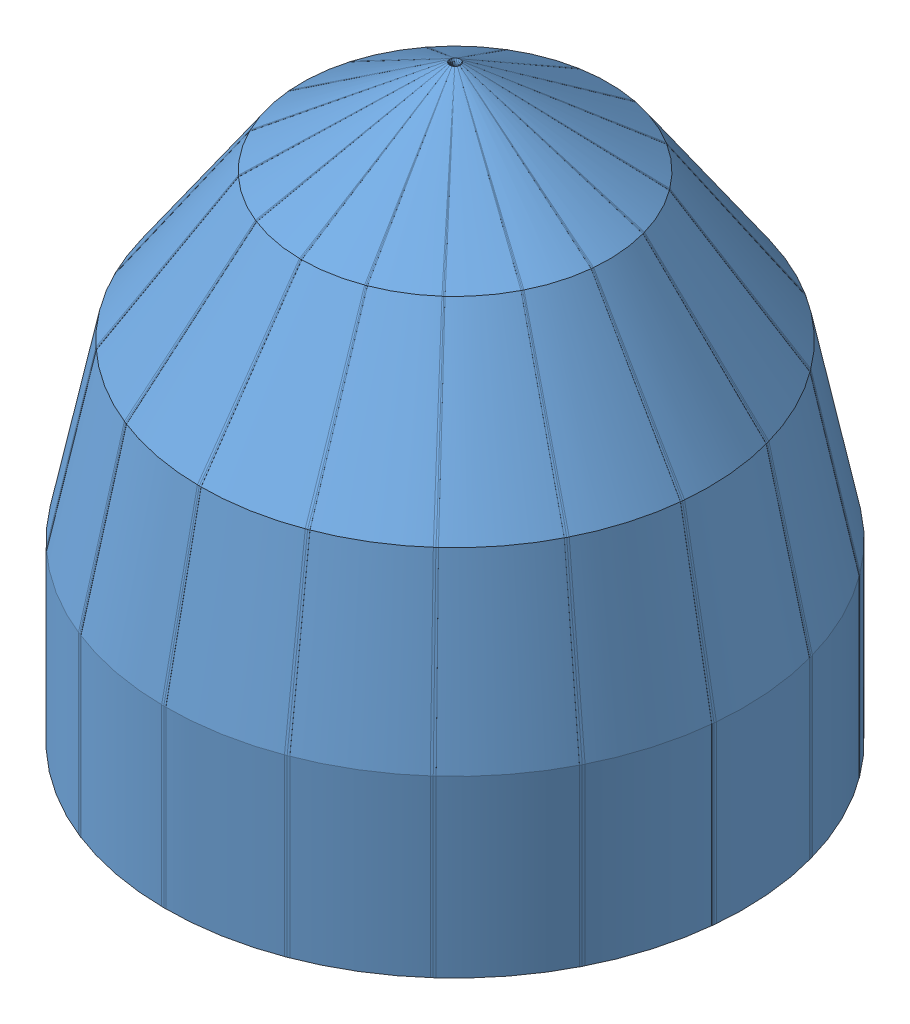
SolidWorks assembly Assem3, configuration Default. Lengths in mm.
Overall size (3151.78 3015.97 3141.58).
68 component instances, 3 part files, 0 mates.
Components (placement in the parent):
- Assem1-1: Assem1 [Default] at (1103.0345 -411.2974 -304.9237) size (563.93 3015.97 1482.16)
  - Part1-1: Part1 [Default] at (643.5811 535.4134 3088.0664) size (555.23 3015.97 1482.16)
  - steel 1-1: steel 1 [Default] at (103.5995 535.4134 2992.4104) x (0.927184 0 0.374607) z (-0.374607 0 0.927184) size (50 2898.58 1340.95)
  - steel 2-1: steel 2 [Default] at (643.5811 535.4134 3097.3722) x (0 0 -1) z (1 0 0) size (1340.95 2898.58 50)
- Assem1-2: Assem1 [Default] at (1744.6774 -411.2974 -425.5922) x (0.932472 0 0.361242) z (-0.361242 0 0.932472) size (563.93 3015.97 1482.16)
  - Part1-1: Part1 [Default] at (643.5811 535.4134 3088.0664) size (555.23 3015.97 1482.16)
  - steel 1-1: steel 1 [Default] at (103.5995 535.4134 2992.4104) x (0.927184 0 0.374607) z (-0.374607 0 0.927184) size (50 2898.58 1340.95)
  - steel 2-1: steel 2 [Default] at (643.5811 535.4134 3097.3722) x (0 0 -1) z (1 0 0) size (1340.95 2898.58 50)
- Assem1-3: Assem1 [Default] at (2386.5821 -411.2974 -306.3241) x (0.739009 0 0.673696) z (-0.673696 0 0.739009) size (563.93 3015.97 1482.16)
  - Part1-1: Part1 [Default] at (643.5811 535.4134 3088.0664) size (555.23 3015.97 1482.16)
  - steel 1-1: steel 1 [Default] at (103.5995 535.4134 2992.4104) x (0.927184 0 0.374607) z (-0.374607 0 0.927184) size (50 2898.58 1340.95)
  - steel 2-1: steel 2 [Default] at (643.5811 535.4134 3097.3722) x (0 0 -1) z (1 0 0) size (1340.95 2898.58 50)
- Assem1-4: Assem1 [Default] at (2942.0558 -411.2974 36.7729) x (0.445738 0 0.895163) z (-0.895163 0 0.445738) size (563.93 3015.97 1482.16)
  - Part1-1: Part1 [Default] at (643.5811 535.4134 3088.0664) size (555.23 3015.97 1482.16)
  - steel 1-1: steel 1 [Default] at (103.5995 535.4134 2992.4104) x (0.927184 0 0.374607) z (-0.374607 0 0.927184) size (50 2898.58 1340.95)
  - steel 2-1: steel 2 [Default] at (643.5811 535.4134 3097.3722) x (0 0 -1) z (1 0 0) size (1340.95 2898.58 50)
- Assem1-5: Assem1 [Default] at (3336.0786 -411.2974 557.3615) x (0.092268 0 0.995734) z (-0.995734 0 0.092268) size (563.93 3015.97 1482.16)
  - Part1-1: Part1 [Default] at (643.5811 535.4134 3088.0664) size (555.23 3015.97 1482.16)
  - steel 1-1: steel 1 [Default] at (103.5995 535.4134 2992.4104) x (0.927184 0 0.374607) z (-0.374607 0 0.927184) size (50 2898.58 1340.95)
  - steel 2-1: steel 2 [Default] at (643.5811 535.4134 3097.3722) x (0 0 -1) z (1 0 0) size (1340.95 2898.58 50)
- Assem1-6: Assem1 [Default] at (3515.4357 -411.2974 1185.1334) x (-0.273663 0 0.961826) z (-0.961826 0 -0.273663) size (563.93 3015.97 1482.16)
  - Part1-1: Part1 [Default] at (643.5811 535.4134 3088.0664) size (555.23 3015.97 1482.16)
  - steel 1-1: steel 1 [Default] at (103.5995 535.4134 2992.4104) x (0.927184 0 0.374607) z (-0.374607 0 0.927184) size (50 2898.58 1340.95)
  - steel 2-1: steel 2 [Default] at (643.5811 535.4134 3097.3722) x (0 0 -1) z (1 0 0) size (1340.95 2898.58 50)
- Assem1-7: Assem1 [Default] at (3455.9038 -411.2974 1835.3045) x (-0.602635 0 0.798017) z (-0.798017 0 -0.602635) size (563.93 3015.97 1482.16)
  - Part1-1: Part1 [Default] at (643.5811 535.4134 3088.0664) size (555.23 3015.97 1482.16)
  - steel 1-1: steel 1 [Default] at (103.5995 535.4134 2992.4104) x (0.927184 0 0.374607) z (-0.374607 0 0.927184) size (50 2898.58 1340.95)
  - steel 2-1: steel 2 [Default] at (643.5811 535.4134 3097.3722) x (0 0 -1) z (1 0 0) size (1340.95 2898.58 50)
- Assem1-8: Assem1 [Default] at (3165.5231 -411.2974 2420.0656) x (-0.850217 0 0.526432) z (-0.526432 0 -0.850217) size (563.93 3015.97 1482.16)
  - Part1-1: Part1 [Default] at (643.5811 535.4134 3088.0664) size (555.23 3015.97 1482.16)
  - steel 1-1: steel 1 [Default] at (103.5995 535.4134 2992.4104) x (0.927184 0 0.374607) z (-0.374607 0 0.927184) size (50 2898.58 1340.95)
  - steel 2-1: steel 2 [Default] at (643.5811 535.4134 3097.3722) x (0 0 -1) z (1 0 0) size (1340.95 2898.58 50)
- Assem1-9: Assem1 [Default] at (2683.5111 -411.2974 2860.4415) x (-0.982973 0 0.18375) z (-0.18375 0 -0.982973) size (563.93 3015.97 1482.16)
  - Part1-1: Part1 [Default] at (643.5811 535.4134 3088.0664) size (555.23 3015.97 1482.16)
  - steel 1-1: steel 1 [Default] at (103.5995 535.4134 2992.4104) x (0.927184 0 0.374607) z (-0.374607 0 0.927184) size (50 2898.58 1340.95)
  - steel 2-1: steel 2 [Default] at (643.5811 535.4134 3097.3722) x (0 0 -1) z (1 0 0) size (1340.95 2898.58 50)
- Assem1-10: Assem1 [Default] at (2074.9661 -411.2974 3096.9569) x (-0.982973 0 -0.18375) z (0.18375 0 -0.982973) size (563.93 3015.97 1482.16)
  - Part1-1: Part1 [Default] at (643.5811 535.4134 3088.0664) size (555.23 3015.97 1482.16)
  - steel 1-1: steel 1 [Default] at (103.5995 535.4134 2992.4104) x (0.927184 0 0.374607) z (-0.374607 0 0.927184) size (50 2898.58 1340.95)
  - steel 2-1: steel 2 [Default] at (643.5811 535.4134 3097.3722) x (0 0 -1) z (1 0 0) size (1340.95 2898.58 50)
- Assem1-11: Assem1 [Default] at (1422.0756 -411.2974 3097.6692) x (-0.850217 0 -0.526432) z (0.526432 0 -0.850217) size (563.93 3015.97 1482.16)
  - Part1-1: Part1 [Default] at (643.5811 535.4134 3088.0664) size (555.23 3015.97 1482.16)
  - steel 1-1: steel 1 [Default] at (103.5995 535.4134 2992.4104) x (0.927184 0 0.374607) z (-0.374607 0 0.927184) size (50 2898.58 1340.95)
  - steel 2-1: steel 2 [Default] at (643.5811 535.4134 3097.3722) x (0 0 -1) z (1 0 0) size (1340.95 2898.58 50)
- Assem1-12: Assem1 [Default] at (813.0161 -411.2974 2862.4822) x (-0.602635 0 -0.798017) z (0.798017 0 -0.602635) size (563.93 3015.97 1482.16)
  - Part1-1: Part1 [Default] at (643.5811 535.4134 3088.0664) size (555.23 3015.97 1482.16)
  - steel 1-1: steel 1 [Default] at (103.5995 535.4134 2992.4104) x (0.927184 0 0.374607) z (-0.374607 0 0.927184) size (50 2898.58 1340.95)
  - steel 2-1: steel 2 [Default] at (643.5811 535.4134 3097.3722) x (0 0 -1) z (1 0 0) size (1340.95 2898.58 50)
- Assem1-13: Assem1 [Default] at (330.0443 -411.2974 2423.1591) x (-0.273663 0 -0.961826) z (0.961826 0 -0.273663) size (563.93 3015.97 1482.16)
  - Part1-1: Part1 [Default] at (643.5811 535.4134 3088.0664) size (555.23 3015.97 1482.16)
  - steel 1-1: steel 1 [Default] at (103.5995 535.4134 2992.4104) x (0.927184 0 0.374607) z (-0.374607 0 0.927184) size (50 2898.58 1340.95)
  - steel 2-1: steel 2 [Default] at (643.5811 535.4134 3097.3722) x (0 0 -1) z (1 0 0) size (1340.95 2898.58 50)
- Assem1-14: Assem1 [Default] at (38.3883 -411.2974 1839.033) x (0.092268 0 -0.995734) z (0.995734 0 0.092268) size (563.93 3015.97 1482.16)
  - Part1-1: Part1 [Default] at (643.5811 535.4134 3088.0664) size (555.23 3015.97 1482.16)
  - steel 1-1: steel 1 [Default] at (103.5995 535.4134 2992.4104) x (0.927184 0 0.374607) z (-0.374607 0 0.927184) size (50 2898.58 1340.95)
  - steel 2-1: steel 2 [Default] at (643.5811 535.4134 3097.3722) x (0 0 -1) z (1 0 0) size (1340.95 2898.58 50)
- Assem1-15: Assem1 [Default] at (-22.5621 -411.2974 1188.9933) x (0.445738 0 -0.895163) z (0.895163 0 0.445738) size (563.93 3015.97 1482.16)
  - Part1-1: Part1 [Default] at (643.5811 535.4134 3088.0664) size (555.23 3015.97 1482.16)
  - steel 1-1: steel 1 [Default] at (103.5995 535.4134 2992.4104) x (0.927184 0 0.374607) z (-0.374607 0 0.927184) size (50 2898.58 1340.95)
  - steel 2-1: steel 2 [Default] at (643.5811 535.4134 3097.3722) x (0 0 -1) z (1 0 0) size (1340.95 2898.58 50)
- Assem1-16: Assem1 [Default] at (155.4248 -411.2974 560.8315) x (0.739009 0 -0.673696) z (0.673696 0 0.739009) size (563.93 3015.97 1482.16)
  - Part1-1: Part1 [Default] at (643.5811 535.4134 3088.0664) size (555.23 3015.97 1482.16)
  - steel 1-1: steel 1 [Default] at (103.5995 535.4134 2992.4104) x (0.927184 0 0.374607) z (-0.374607 0 0.927184) size (50 2898.58 1340.95)
  - steel 2-1: steel 2 [Default] at (643.5811 535.4134 3097.3722) x (0 0 -1) z (1 0 0) size (1340.95 2898.58 50)
- Assem1-17: Assem1 [Default] at (548.3108 -411.2974 39.3844) x (0.932472 0 -0.361242) z (0.361242 0 0.932472) size (563.93 3015.97 1482.16)
  - Part1-1: Part1 [Default] at (643.5811 535.4134 3088.0664) size (555.23 3015.97 1482.16)
  - steel 1-1: steel 1 [Default] at (103.5995 535.4134 2992.4104) x (0.927184 0 0.374607) z (-0.374607 0 0.927184) size (50 2898.58 1340.95)
  - steel 2-1: steel 2 [Default] at (643.5811 535.4134 3097.3722) x (0 0 -1) z (1 0 0) size (1340.95 2898.58 50)
